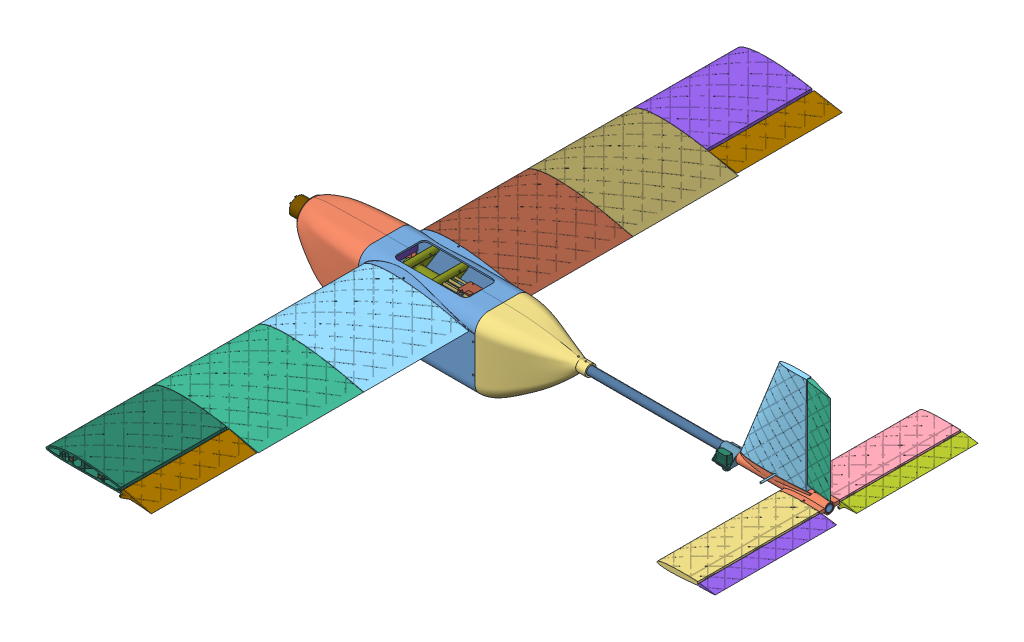
SolidWorks assembly Assembly, configuration Default. Lengths in mm.
Overall size (1354.4 354.34 1422).
45 component instances, 37 part files, 89 mates.
Components (placement in the parent):
- FusBody3mm-1: FusBody3mm [Default] at (-54.3367 236.4946 192.8797) size (251.69 161.84 138.59)
- FusNose3mm-1: FusNose3mm [Default] at (-44.3367 236.4946 192.8797) size (160.99 149.52 118.24)
- FusTail-1: FusTail [Default] at (-64.3367 236.4946 192.8797) size (188.23 160.96 132.13)
- CarbonTube8x6x1000mm-1: CarbonTube8x6x1000mm [Default] at (6.8096 247.6052 192.8797) x (-0.006313 -0.99998 0) z (0 0 1) size (8 8 1000)
- CarbonTube8x6x1000mm-2: CarbonTube8x6x1000mm [Default] at (66.8007 246.303 192.8797) x (0.417427 -0.90871 0) z (0 0 1) size (8 8 1000)
- WingSection1L-2: WingSection1L [Default] at (-44.3406 242.2988 361.3797) x (0.999393 -0.034839 0) z (0 0 1) size (221.89 24.62 224)
- WingSection2L-2: WingSection2L [Default] at (-44.3406 242.2988 578.3797) x (0.999393 -0.034839 0) z (0 0 1) size (221.89 24.62 217)
- CarbonTube6x4x500mm-1: CarbonTube6x4x500mm [Default] at (6.8096 247.6052 653.8797) x (0.820995 -0.570935 0) z (0 0 1) size (6 6 500)
- CarbonTube6x4x500mm-2: CarbonTube6x4x500mm [Default] at (66.8007 246.303 653.8797) x (0.220629 -0.975358 0) z (0 0 1) size (6 6 500)
- WingSection3L____-1: WingSection3L____ [Default] at (-44.3406 242.2988 -409.6203) x (0.999393 -0.034839 0) z (0 0 1) size (155.89 33.53 217)
- Aileron-1: Aileron [Default] at (-47.293 246.5907 795.3797) x (0.998066 -0.062165 0) z (0 0 1) size (65.5 17.6 217)
- TailSpar16x14x1000mm-1: TailSpar16x14x1000mm [Default] at (357.0071 229.7725 192.8797) x (0 0.093029 0.995663) z (1 0 0) size (16 16 1000)
- WingSection1R-1: WingSection1R [Default] at (-44.3406 242.2988 255.3797) x (0.999393 -0.034839 0) z (0 0 1) size (221.89 24.62 224)
- WingSection2R-1: WingSection2R [Default] at (-44.3406 242.2988 -192.6203) x (0.999393 -0.034839 0) z (0 0 1) size (221.89 24.62 217)
- Servo-1: Servo [Default] at (26.6848 243.6741 858.2141) x (0.999393 -0.034839 0) z (-0.034839 -0.999393 0) size (29.9 31.7 12.6)
- ServoCup-1: ServoCup [Default] at (97.8135 248.0164 795.3797) x (-0.999393 0.034839 0) z (0 0 -1) size (30.9 13 63.42)
- WingSection3R____-1: WingSection3R____ [Default] at (-44.3406 242.2988 1012.3797) x (0.999393 -0.034839 0) z (0 0 1) size (155.89 33.53 217)
- WingConnector2-1: WingConnector2 [Default] at (7.0071 247.6025 192.8797) size (98.1 34.63 80)
- MotorMount-1: MotorMount [Default] at (-208.7993 220.3141 192.8797) x (0 -0.707107 -0.707107) z (1 0 0) size (52 52 3)
- Sunnysky_2814_BrushlessMotor-1: Sunnysky_2814_BrushlessMotor [Varsayılan] at (-246.2993 217.868 188.6679) x (0 0.495555 -0.868576) z (1 0 0) size (35 35 54)
- ESC60A-1: ESC60A [Default] at (-107.4638 247.6725 188.8175) x (0.999957 0 0.009298) z (0 -1 0) size (77 35 15)
- TailConnector-1: TailConnector [Default] at (764.8695 229.7725 192.8797) size (191.54 26 41)
- TailL-1: TailL [Default] at (772.5985 227.6665 338.3797) x (0.999391 0.034899 0) z (0 0 1) size (95.69 12.53 257)
- TailR-1: TailR [Default] at (772.5985 227.6665 311.3797) x (0.999391 0.034899 0) z (0 0 1) size (95.69 12.53 257)
- CarbonTube6x4x500mm-3: CarbonTube6x4x500mm [Default] at (804.5134 228.781 173.1797) x (-0.391278 0.920272 0) z (0 0 1) size (6 6 500)
- CarbonTube6x4x500mm-4: CarbonTube6x4x500mm [Default] at (839.4921 230.0025 173.1797) x (0.696448 -0.717607 0) z (0 0 1) size (6 6 500)
- VerticalTailSection-1: VerticalTailSection [Default] at (674.8652 240.2725 192.8797) size (147.44 200.2 70)
- Rudder-1: Rudder [Default] at (677.8553 240.2725 162.8758) x (0.975763 0 0.218831) z (-0.218831 0 0.975763) size (89.77 185.08 21.9)
- ElevatorR-1: ElevatorR [Default] at (772.4937 234.5914 47.3797) x (0.998511 -0.054548 0) z (0 0 1) size (45.8 15.57 250)
- ElevatorL-1: ElevatorL [Default] at (772.4937 234.5914 88.3797) x (0.998511 -0.054548 0) z (0 0 1) size (45.8 15.57 250)
- AileronLeft-1: AileronLeft [Default] at (-47.1428 234.7012 -626.6203) x (0.999909 0.013495 0) z (0 0 1) size (65.5 17.6 217)
- FC_MatekF405WMN-1: FC_MatekF405WMN [Default] at (120.8073 242.1725 192.8797) x (0 0 1) z (0 -1 0) size (28 61 18.85)
  - FCScrew-1: FCScrew [Default] at (11 8.5 -4.2) x (-0.400084 -0.916479 0) z (0 0 1) size (3 3 6.8)
  - MatekF405WMNFC-1: MatekF405WMNFC [Default] at (0 0 -7.6) x (-1 0 0) z (0 0 -1) size (28 31 5)
  - MatekF405WMNPDB-1: MatekF405WMNPDB [Default] at origin size (27.5 61 6.6)
  - FCScrew-2: FCScrew [Default] at (11 -13.5 -4.2) x (-0.99923 -0.039246 0) z (0 0 1) size (3 3 6.8)
  - FCScrew-3: FCScrew [Default] at (-11 8.5 -4.2) x (-0.400084 -0.916479 0) z (0 0 1) size (3 3 6.8)
  - FCScrew-4: FCScrew [Default] at (-11 -13.5 -4.2) x (-0.400084 -0.916479 0) z (0 0 1) size (3 3 6.8)
- FC_Mounting-1: FC_Mounting [Default] at (120.8073 239.7725 192.8797) x (1 0 0) z (0 1 0) size (33.8 30.8 24)
- ServoDascket-1: ServoDascket [Default] at (657.3695 229.7725 192.8797) x (0 0 1) z (-1 0 0) size (41.49 21 35)
- MicroServo-SG90.step-1: MicroServo-SG90.step [Default] at (657.5867 239.0725 209.9297) x (1 0 0) z (0 -1 0) size (32.6 12.36 29.8)
- lipobattery-1: lipobattery [Default] at (-112.4428 197.8725 194.5797) x (1 0 0) z (0 -1 0) size (136 41 19)
- transmitter-1: transmitter [Default] at (-26.9455 250.1502 192.8797) x (0 0 -1) z (0 1 0) size (47 27 15)
- BatteryHolder2-1: BatteryHolder2 [Default] at (-107.9929 229.7725 192.8797) x (0 0 1) z (-1 0 0) size (50.4 54.8 70)
- Cargo2-1: Cargo2 [Default] at (-129.0314 170.1117 192.2349) size (50 30 50)
Mates (geometry in assembly coordinates):
- Концентричный1: concentric aligned: cylinder of FusBody3mm-1 through (-50.3367 217.7754 128.5898) axis (0 0 1) radius 1.6; cylinder of FusNose3mm-1 through (-50.3367 217.7754 133.442) axis (0 0 1) radius 1.6
- Концентричный2: concentric aligned: cylinder of FusBody3mm-1 through (181.6633 217.7754 128.5898) axis (0 0 1) radius 1.6; cylinder of FusTail-1 through (181.6633 217.7754 130.4171) axis (0 0 1) radius 1.6
- Расстояние1: distance = 440 mm aligned: plane of CarbonTube8x6x1000mm-1 through (6.8096 247.6052 -307.1203) normal (0 0 -1); plane of FusBody3mm-1 through (64.4199 255.8548 132.8797) normal (0 0 -1)
- Концентричный15: concentric aligned: cylinder of FusBody3mm-1 through (66.8007 246.303 134.8797) axis (0 0 -1) radius 4.3; cylinder of CarbonTube8x6x1000mm-2 through (66.8007 246.303 692.8797) axis (0 0 -1) radius 4
- Расстояние2: distance = 440 mm aligned: plane of FusBody3mm-1 through (64.4199 255.8548 132.8797) normal (0 0 -1); plane of CarbonTube8x6x1000mm-2 through (66.8007 246.303 -307.1203) normal (0 0 -1)
- Концентричный16: concentric anti-aligned: cylinder of CarbonTube8x6x1000mm-1 through (6.8096 247.6052 692.8797) axis (0 0 -1) radius 4; cylinder of WingSection1L-2 through (6.8097 247.6052 252.8797) axis (0 0 1) radius 4.35
- Концентричный17: concentric anti-aligned: cylinder of CarbonTube8x6x1000mm-2 through (66.8007 246.303 692.8797) axis (0 0 -1) radius 4; cylinder of WingSection1L-2 through (66.8007 246.303 252.8797) axis (0 0 1) radius 4.35
- Совпадение25: coincident anti-aligned: plane of FusBody3mm-1 through (64.4199 255.8548 252.8797) normal (0 0 1); plane of WingSection1L-2 through (139.8548 273.4004 252.8797) normal (0 0 -1)
- Концентричный18: concentric anti-aligned: cylinder of CarbonTube8x6x1000mm-1 through (6.8096 247.6052 692.8797) axis (0 0 -1) radius 4; cylinder of WingSection2L-2 through (6.8097 247.6052 469.8797) axis (0 0 1) radius 4.35
- Концентричный19: concentric anti-aligned: cylinder of CarbonTube8x6x1000mm-2 through (66.8007 246.303 692.8797) axis (0 0 -1) radius 4; cylinder of WingSection2L-2 through (66.8007 246.303 469.8797) axis (0 0 1) radius 4.35
- Совпадение26: coincident anti-aligned: plane of WingSection1L-2 through (139.8548 273.4004 469.8797) normal (0 0 1); plane of WingSection2L-2 through (139.8548 273.4004 469.8797) normal (0 0 -1)
- Концентричный22: concentric aligned: cylinder of FusBody3mm-1 through (6.8096 247.6052 134.8797) axis (0 0 -1) radius 4.3; cylinder of CarbonTube8x6x1000mm-1 through (6.8096 247.6052 692.8797) axis (0 0 -1) radius 4
- Концентричный23: concentric aligned: cylinder of CarbonTube8x6x1000mm-1 through (6.8096 247.6052 692.8797) axis (0 0 -1) radius 3; cylinder of CarbonTube6x4x500mm-1 through (6.8096 247.6052 903.8797) axis (0 0 -1) radius 3
- Концентричный24: concentric aligned: cylinder of CarbonTube8x6x1000mm-2 through (66.8007 246.303 692.8797) axis (0 0 -1) radius 3; cylinder of CarbonTube6x4x500mm-2 through (66.8007 246.303 903.8797) axis (0 0 -1) radius 3
- Параллельность1: parallel aligned: plane of FusNose3mm-1 through (-207.2993 219.7725 224.8558) normal (-1 0 0); plane of TailSpar16x14x1000mm-1 through (-142.9929 229.7725 192.8797) normal (-1 0 0)
- Концентричный29: concentric aligned: cylinder of CarbonTube8x6x1000mm-1 through (6.8096 247.6052 692.8797) axis (0 0 -1) radius 4; cylinder of WingSection1R-1 through (6.8097 247.6052 132.8797) axis (0 0 -1) radius 4.35
- Концентричный30: concentric aligned: cylinder of CarbonTube8x6x1000mm-2 through (66.8007 246.303 692.8797) axis (0 0 -1) radius 4; cylinder of WingSection1R-1 through (66.8007 246.303 132.8797) axis (0 0 -1) radius 4.35
- Совпадение33: coincident anti-aligned: plane of FusBody3mm-1 through (64.4199 255.8548 132.8797) normal (0 0 -1); plane of WingSection1R-1 through (139.8548 273.4004 132.8797) normal (0 0 1)
- Концентричный31: concentric anti-aligned: cylinder of CarbonTube8x6x1000mm-1 through (6.8096 247.6052 692.8797) axis (0 0 -1) radius 4; cylinder of WingSection2R-1 through (6.8097 247.6052 -301.1203) axis (0 0 1) radius 4.35
- Концентричный32: concentric anti-aligned: cylinder of CarbonTube8x6x1000mm-2 through (66.8007 246.303 692.8797) axis (0 0 -1) radius 4; cylinder of WingSection2R-1 through (66.8007 246.303 -301.1203) axis (0 0 1) radius 4.35
- Совпадение34: coincident anti-aligned: plane of WingSection1R-1 through (139.8548 273.4004 -84.1203) normal (0 0 -1); plane of WingSection2R-1 through (139.8548 273.4004 -84.1203) normal (0 0 1)
- Совпадение39: coincident anti-aligned: plane of Servo-1 through (26.4653 237.3779 858.2141) normal (-0.034839 -0.999393 0); plane of ServoCup-1 through (97.3565 234.9066 795.3797) normal (0.034839 0.999393 0)
- Совпадение40: coincident anti-aligned: plane of Servo-1 through (14.8223 237.7838 846.3641) normal (0 0 -1); plane of ServoCup-1 through (97.7746 246.8993 846.3641) normal (0 0 1)
- Расстояние3: distance = 0.5 mm aligned: plane of Servo-1 through (41.4062 236.8571 863.3641) normal (0.999393 -0.034839 0); plane of ServoCup-1 through (41.9059 236.8397 795.3797) normal (0.999393 -0.034839 0)
- Концентричный36: concentric aligned: cylinder of CarbonTube8x6x1000mm-1 through (6.8096 247.6052 692.8797) axis (0 0 -1) radius 4; cylinder of WingSection3R____-1 through (6.8097 247.6052 903.8797) axis (0 0 -1) radius 4.35
- Концентричный37: concentric aligned: cylinder of CarbonTube8x6x1000mm-2 through (66.8007 246.303 692.8797) axis (0 0 -1) radius 4; cylinder of WingSection3R____-1 through (66.8007 246.303 903.8797) axis (0 0 -1) radius 4.35
- Совпадение43: coincident anti-aligned: plane of WingSection2L-2 through (139.8548 273.4004 686.8797) normal (0 0 1); plane of WingSection3R____-1 through (139.8548 273.4004 686.8797) normal (0 0 -1)
- Концентричный38: concentric anti-aligned: cylinder of CarbonTube8x6x1000mm-1 through (6.8096 247.6052 692.8797) axis (0 0 -1) radius 4; cylinder of WingSection3L____-1 through (6.8097 247.6052 -518.1203) axis (0 0 1) radius 4.35
- Концентричный39: concentric anti-aligned: cylinder of CarbonTube8x6x1000mm-2 through (66.8007 246.303 692.8797) axis (0 0 -1) radius 4; cylinder of WingSection3L____-1 through (66.8007 246.303 -518.1203) axis (0 0 1) radius 4.35
- Совпадение45: coincident anti-aligned: plane of WingSection3L____-1 through (139.8548 273.4004 -301.1203) normal (0 0 1); plane of WingSection2R-1 through (139.8548 273.4004 -301.1203) normal (0 0 -1)
- Совпадение47: coincident aligned: line of ServoCup-1 through (26.8833 249.3706 815.9454) axis (-0.034839 -0.999393 0); line of WingSection3R____-1 through (26.895 249.7037 815.9454) axis (-0.034839 -0.999393 0)
- Концентричный48: concentric anti-aligned: cylinder of TailSpar16x14x1000mm-1 through (857.0071 229.7725 192.8797) axis (-1 0 0) radius 8; cylinder of WingConnector2-1 through (-12.9929 229.7725 192.8797) axis (1 0 0) radius 8.5
- Параллельность7: parallel aligned: cylinder of CarbonTube8x6x1000mm-2 through (66.8007 246.303 692.8797) axis (0 0 -1) radius 4; cylinder of WingConnector2-1 through (66.9971 247.6025 232.8797) axis (0 0 -1) radius 4.3
- Совпадение49: coincident anti-aligned: plane of FusNose3mm-1 through (-207.2993 219.7725 224.8558) normal (-1 0 0); plane of MotorMount-1 through (-207.2993 235.8705 208.436) normal (1 0 0)
- Концентричный50: concentric aligned: cylinder of FusNose3mm-1 through (-46.3217 235.8705 208.436) axis (-1 0 0) radius 1.6; cylinder of MotorMount-1 through (-207.2993 235.8705 208.436) axis (-1 0 0) radius 1.6
- Концентричный51: concentric aligned: cylinder of FusNose3mm-1 through (-46.3217 204.7578 177.3233) axis (-1 0 0) radius 1.6; cylinder of MotorMount-1 through (-207.2993 204.7578 177.3233) axis (-1 0 0) radius 1.6
- Совпадение50: coincident anti-aligned: plane of MotorMount-1 through (-210.2993 235.8705 208.436) normal (-1 0 0); plane of Sunnysky_2814_BrushlessMotor-1 through (-210.2993 217.868 188.6679) normal (1 0 0)
- Концентричный55: concentric anti-aligned: cylinder of MotorMount-1 through (-207.2993 227.0316 186.1622) axis (-1 0 0) radius 1.6; cylinder of Sunnysky_2814_BrushlessMotor-1 through (-213.2993 227.0316 186.1622) axis (1 0 0) radius 1.6
- Совпадение51: coincident anti-aligned: plane of FusBody3mm-1 through (-54.3367 236.4946 192.8797) normal (-1 0 0); plane of FusNose3mm-1 through (-54.3367 260.7754 192.8797) normal (1 0 0)
- Совпадение52: coincident anti-aligned: plane of FusBody3mm-1 through (185.6633 236.4946 192.8797) normal (1 0 0); plane of FusTail-1 through (185.6633 260.7754 192.8797) normal (-1 0 0)
- Совпадение53: coincident aligned: line of ServoCup-1 through (41.9059 236.8397 879.3641) axis (0 0 -1); line of WingSection3R____-1 through (41.9059 236.8397 879.3641) axis (0 0 -1)
- Совпадение54: coincident aligned: plane of Aileron-1 through (137.6842 272.6419 903.8797) normal (0 0 1); plane of WingSection3R____-1 through (139.8548 273.4004 903.8797) normal (0 0 1)
- Совпадение56: coincident anti-aligned: line of Aileron-1 through (109.7645 242.6289 896.3797) axis (0 0 1); line of WingSection3R____-1 through (109.7645 242.6289 896.3797) axis (0 0 -1)
- Концентричный61: concentric aligned: cylinder of TailL-1 through (804.5134 228.781 463.3797) axis (0 0 -1) radius 4; cylinder of CarbonTube6x4x500mm-3 through (804.5134 228.781 423.1797) axis (0 0 -1) radius 3
- Концентричный62: concentric aligned: cylinder of TailL-1 through (839.4921 230.0025 463.3797) axis (0 0 -1) radius 4; cylinder of CarbonTube6x4x500mm-4 through (839.4921 230.0025 423.1797) axis (0 0 -1) radius 3
- Концентричный63: concentric anti-aligned: cylinder of TailConnector-1 through (804.5134 228.781 172.3797) axis (0 0 1) radius 3.4; cylinder of CarbonTube6x4x500mm-3 through (804.5134 228.781 423.1797) axis (0 0 -1) radius 3
- Концентричный65: concentric anti-aligned: cylinder of TailConnector-1 through (839.4921 230.0025 172.3797) axis (0 0 1) radius 3.4; cylinder of CarbonTube6x4x500mm-4 through (839.4921 230.0025 423.1797) axis (0 0 -1) radius 3
- Совпадение63: coincident anti-aligned: plane of TailConnector-1 through (764.8695 229.7725 213.3797) normal (0 0 1); plane of TailL-1 through (802.0568 243.7044 213.3797) normal (0 0 -1)
- Концентричный66: concentric aligned: cylinder of TailConnector-1 through (804.5134 228.781 172.3797) axis (0 0 1) radius 3.4; cylinder of TailR-1 through (804.5134 228.781 -77.6203) axis (0 0 1) radius 4
- Концентричный67: concentric aligned: cylinder of TailConnector-1 through (839.4921 230.0025 172.3797) axis (0 0 1) radius 3.4; cylinder of TailR-1 through (839.4921 230.0025 -77.6203) axis (0 0 1) radius 4
- Совпадение64: coincident anti-aligned: plane of TailConnector-1 through (764.8695 229.7725 172.3797) normal (0 0 -1); plane of TailR-1 through (802.0568 243.7044 172.3797) normal (0 0 1)
- Концентричный68: concentric anti-aligned: cylinder of TailConnector-1 through (724.2995 230.2725 192.8797) axis (0 1 0) radius 3.4; cylinder of VerticalTailSection-1 through (724.2995 340.2725 192.8797) axis (0 -1 0) radius 3.95
- Концентричный69: concentric anti-aligned: cylinder of TailConnector-1 through (784.2995 230.2725 192.8797) axis (0 1 0) radius 3.4; cylinder of VerticalTailSection-1 through (784.2995 430.2725 192.8797) axis (0 -1 0) radius 3.95
- Совпадение66: coincident aligned: plane of TailR-1 through (840.9017 245.0609 -77.6203) normal (0 0 -1); plane of ElevatorR-1 through (873.163 244.1143 -77.6203) normal (0 0 -1)
- Совпадение68: coincident aligned: plane of VerticalTailSection-1 through (763.7338 440.2725 207.8797) normal (0 1 0); plane of Rudder-1 through (819.8333 440.2725 210.0893) normal (0 1 0)
- Совпадение70: coincident anti-aligned: line of TailR-1 through (856.5683 229.9985 157.3797) axis (0 0 -1); line of ElevatorR-1 through (856.5683 229.9985 57.3797) axis (0 0 1)
- Совпадение71: coincident aligned: plane of TailL-1 through (840.9017 245.0609 463.3797) normal (0 0 1); plane of ElevatorL-1 through (873.163 244.1143 463.3797) normal (0 0 1)
- Совпадение73: coincident aligned: line of TailL-1 through (856.5683 229.9985 448.3797) axis (0 0 -1); line of ElevatorL-1 through (856.5683 229.9985 463.3797) axis (0 0 -1)
- Совпадение74: coincident anti-aligned: line of ElevatorR-1 through (892.315 228.0456 -77.6203) axis (0 0 1); line of ElevatorL-1 through (892.315 228.0456 463.3797) axis (0 0 -1)
- Совпадение76: coincident aligned: line of WingSection3L____-1 through (109.7645 242.6289 -308.6203) axis (0 0 -1); line of AileronLeft-1 through (109.7645 242.6289 -333.6203) axis (0 0 -1)
- Совпадение77: coincident anti-aligned: plane of WingSection2R-1 through (139.8548 273.4004 -301.1203) normal (0 0 -1); plane of AileronLeft-1 through (135.3344 274.6674 -301.1203) normal (0 0 1)
- Совпадение78: coincident anti-aligned: plane of TailConnector-1 through (764.8695 240.2725 192.8797) normal (0 1 0); plane of VerticalTailSection-1 through (674.8652 240.2725 231.8807) normal (0 -1 0)
- Концентричный70: concentric aligned: cylinder of TailSpar16x14x1000mm-1 through (857.0071 229.7725 192.8797) axis (-1 0 0) radius 8; cylinder of FC_Mounting-1 through (166.9915 229.7725 192.8797) axis (-1 0 0) radius 8.4
- Совпадение79: coincident anti-aligned: plane of FC_MatekF405WMN-1/MatekF405WMNPDB-1 through (120.8073 241.3725 192.8797) normal (0 -1 0); plane of FC_Mounting-1 through (120.8073 241.3725 192.8797) normal (0 1 0)
- Концентричный73: concentric aligned: cylinder of FC_MatekF405WMN-1/MatekF405WMNFC-1 through (112.3073 249.7725 203.8797) axis (0 1 0) radius 1; cylinder of FC_Mounting-1 through (112.3073 219.7725 203.8797) axis (0 1 0) radius 1
- Концентричный74: concentric aligned: cylinder of FC_MatekF405WMN-1/MatekF405WMNFC-1 through (112.3073 249.7725 181.8797) axis (0 1 0) radius 1; cylinder of FC_Mounting-1 through (112.3073 219.7725 181.8797) axis (0 1 0) radius 1
- Параллельность9: parallel aligned: plane of FC_MatekF405WMN-1/MatekF405WMNFC-1 through (120.8073 251.7725 192.8797) normal (0 1 0)
- Концентричный75: concentric anti-aligned: cylinder of TailSpar16x14x1000mm-1 through (857.0071 229.7725 192.8797) axis (-1 0 0) radius 8; cylinder of ServoDascket-1 through (639.8695 229.7725 192.8797) axis (1 0 0) radius 8.5
- Совпадение81: coincident anti-aligned: line of VerticalTailSection-1 through (814.2995 425.2725 193.4797) axis (0 -1 0); line of Rudder-1 through (814.2995 425.2725 193.4797) axis (0 1 0)
- Совпадение82: coincident anti-aligned: plane of TailR-1 through (814.1763 223.7438 -76.8203) normal (0 0 1); plane of CarbonTube6x4x500mm-4 through (839.4921 230.0025 -76.8203) normal (0 0 -1)
- Совпадение83: coincident anti-aligned: plane of TailR-1 through (814.1763 223.7438 -76.8203) normal (0 0 1); plane of CarbonTube6x4x500mm-3 through (804.5134 228.781 -76.8203) normal (0 0 -1)
- Совпадение90: coincident anti-aligned: plane of TailConnector-1 through (674.8695 229.7725 192.8797) normal (-1 0 0); plane of ServoDascket-1 through (674.8695 229.7725 192.8797) normal (1 0 0)
- Совпадение91: coincident anti-aligned: plane of ServoDascket-1 through (657.3695 220.4725 176.3854) normal (0 1 0); plane of MicroServo-SG90.step-1 through (657.5867 220.4725 209.9297) normal (0 -1 0)
- Концентричный77: concentric aligned: cylinder of ServoDascket-1 through (643.2867 240.2725 209.9297) axis (0 -1 0) radius 1.25; cylinder of MicroServo-SG90.step-1 through (643.2867 220.4725 209.9297) axis (0 -1 0) radius 1.25
- Концентричный78: concentric aligned: cylinder of ServoDascket-1 through (671.8867 240.2725 209.9297) axis (0 -1 0) radius 1.25; cylinder of MicroServo-SG90.step-1 through (671.8867 220.4725 209.9297) axis (0 -1 0) radius 1.25
- Параллельность14: parallel aligned: plane of MicroServo-SG90.step-1 through (639.4221 239.0725 203.7797) normal (0 1 0)
- Концентричный79: concentric anti-aligned: cylinder of TailSpar16x14x1000mm-1 through (857.0071 229.7725 192.8797) axis (-1 0 0) radius 8; cylinder of TailConnector-1 through (674.8695 229.7725 192.8797) axis (1 0 0) radius 8.5
- Параллельность16: parallel aligned: plane of VerticalTailSection-1 through (763.7338 440.2725 207.8797) normal (0 1 0)
- Расстояние5: distance = 130 mm aligned: plane of WingConnector2-1 through (-12.9929 229.7725 192.8797) normal (-1 0 0); plane of TailSpar16x14x1000mm-1 through (-142.9929 229.7725 192.8797) normal (-1 0 0)
- Совпадение103: coincident aligned: plane of TailSpar16x14x1000mm-1 through (857.0071 229.7725 192.8797) normal (1 0 0); plane of TailConnector-1 through (857.0071 229.7725 192.8797) normal (1 0 0)
- Параллельность20: parallel anti-aligned: plane of transmitter-1 through (-26.9455 250.1502 192.8797) normal (-1 0 0)
- Совпадение105: coincident anti-aligned: plane of FusBody3mm-1 through (-54.3367 236.4946 192.8797) normal (0 0 1); plane of transmitter-1 through (-26.9455 250.1502 192.8797) normal (0 0 -1)
- Концентричный80: concentric anti-aligned: cylinder of FusTail-1 through (364.6633 229.7725 192.8797) axis (1 0 0) radius 6.3818; cylinder of TailSpar16x14x1000mm-1 through (857.0071 229.7725 192.8797) axis (-1 0 0) radius 8
- Концентричный83: concentric anti-aligned: cylinder of TailSpar16x14x1000mm-1 through (857.0071 229.7725 192.8797) axis (-1 0 0) radius 8; cylinder of BatteryHolder2-1 through (-142.9929 229.7725 192.8797) axis (1 0 0) radius 8.4
- Совпадение111: coincident anti-aligned: plane of lipobattery-1 through (-112.4428 188.3725 194.5797) normal (0 -1 0); plane of BatteryHolder2-1 through (-142.9929 188.3725 192.8797) normal (0 1 0)
- Совпадение112: coincident anti-aligned: plane of lipobattery-1 through (-180.4428 188.3725 215.0797) normal (0 0 1); plane of BatteryHolder2-1 through (-142.9929 229.7725 215.0797) normal (0 0 -1)
- Совпадение113: coincident aligned: plane of TailSpar16x14x1000mm-1 through (-142.9929 229.7725 192.8797) normal (-1 0 0); plane of BatteryHolder2-1 through (-142.9929 229.7725 192.8797) normal (-1 0 0)
- Параллельность22: parallel anti-aligned: plane of BatteryHolder2-1 through (-142.9929 185.3725 192.8797) normal (0 -1 0)
- Совпадение114: coincident anti-aligned: plane of ESC60A-1 through (-107.4638 240.1725 188.8175) normal (0 -1 0); plane of BatteryHolder2-1 through (-107.9929 240.1725 192.8797) normal (0 1 0)
